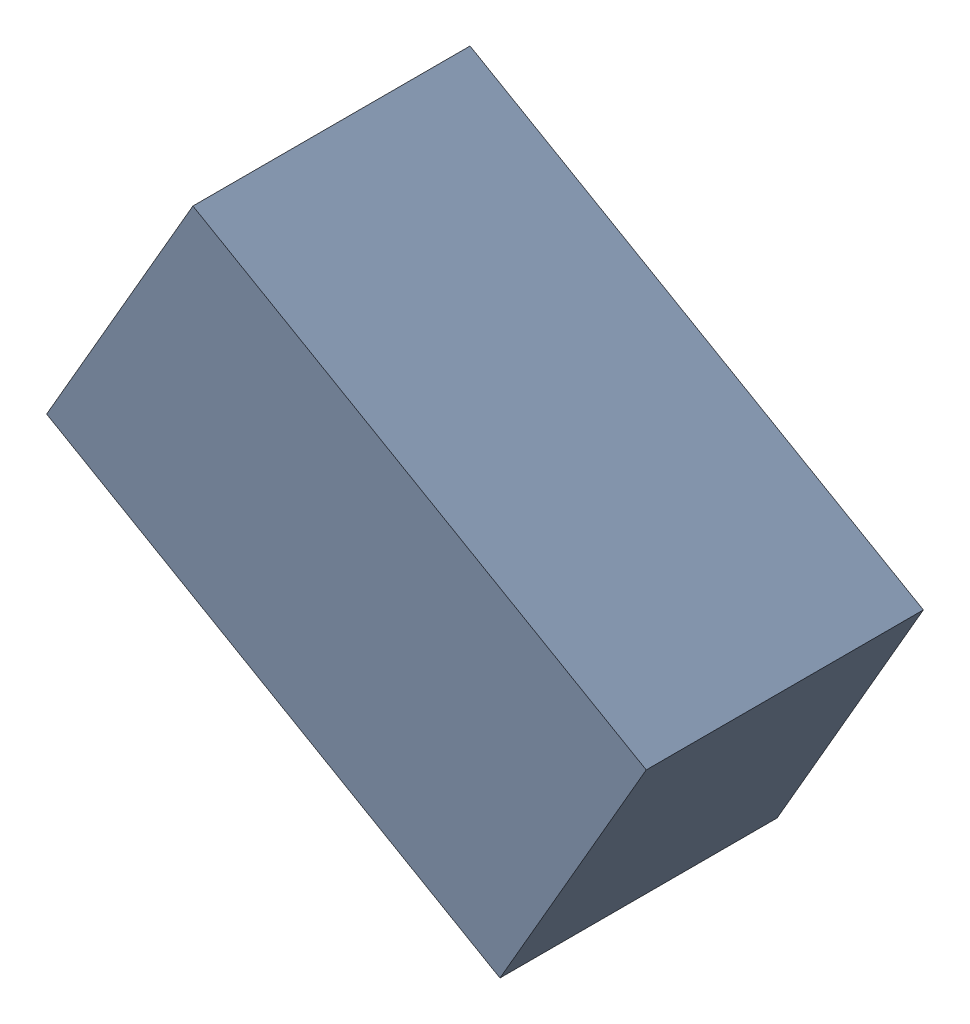
SolidWorks assembly R2_TDA3, configuration Standard. Lengths in mm.
Overall size (1.95 1.67 0.9).
2 component instances, 1 part files, 0 mates.
Components (placement in the parent):
- 885544144-1: 885544144 [Standard] at (47.8969 -23.5316 0) size (1.95 1.67 0.9)
  - Extruded_14-1: Extruded_14 [Standard] at origin size (1.95 1.67 0.9)
